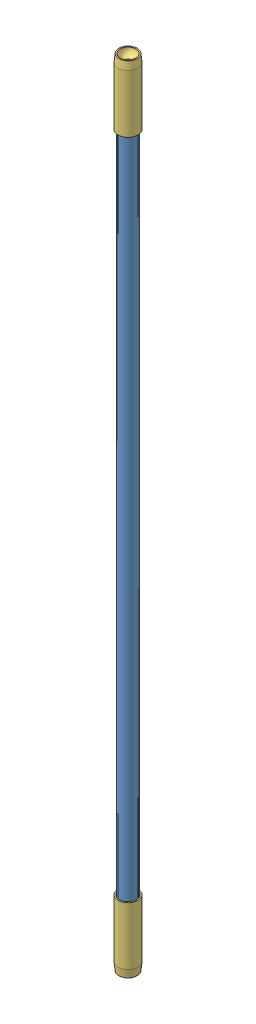
SolidWorks assembly Assem-Arms, configuration Default. Lengths in mm.
Overall size (16.54 480.57 16.54).
5 component instances, 3 part files, 10 mates.
Components (placement in the parent):
- part-dragon plate-carbon fiber tube-1: part-dragon plate-carbon fiber tube [Default] at (208.0008 -4.057 490.0421) size (9.95 452 9.95)
- part-3 8 in magnet-N52-1: part-3 8 in magnet-N52 [Default] at (208.0008 447.943 490.0421) size (9.53 9.53 9.53)
- part-3 8 in magnet-N52-2: part-3 8 in magnet-N52 [Default] at (208.0008 -4.057 490.0421) x (-1 0 0) z (0 0 1) size (9.53 9.53 9.53)
- PlasPrint-arm ends-1: PlasPrint-arm ends [Default] at (208.0008 422.468 490.0421) x (0.979 0 0.203858) z (-0.203858 0 0.979) size (12 39.76 12)
- PlasPrint-arm ends-2: PlasPrint-arm ends [Default] at (208.0008 21.418 490.0421) x (0.531956 0 0.846772) z (0.846772 0 -0.531956) size (12 39.76 12)
Mates (geometry in assembly coordinates):
- Concentric1: concentric aligned: cylinder of part-3 8 in magnet-N52-1 through (208.0008 457.468 490.0421) axis (0 -1 0) radius 4.7625; cylinder of PlasPrint-arm ends-1 through (208.0008 447.468 490.0421) axis (0 -1 0) radius 5.2
- Concentric2: concentric aligned: cylinder of part-3 8 in magnet-N52-1 through (208.0008 457.468 490.0421) axis (0 -1 0) radius 4.7625; cylinder of PlasPrint-arm ends-1 through (208.0008 447.468 490.0421) axis (0 -1 0) radius 6
- Concentric3: concentric aligned: cylinder of part-3 8 in magnet-N52-2 through (208.0008 -13.582 490.0421) axis (0 1 0) radius 4.7625; cylinder of PlasPrint-arm ends-2 through (208.0008 -3.582 490.0421) axis (0 1 0) radius 5.2
- Concentric4: concentric anti-aligned: cylinder of part-dragon plate-carbon fiber tube-1 through (208.0008 447.943 490.0421) axis (0 -1 0) radius 4.975; cylinder of PlasPrint-arm ends-2 through (208.0008 -3.582 490.0421) axis (0 1 0) radius 5.2
- Concentric5: concentric aligned: cylinder of part-dragon plate-carbon fiber tube-1 through (208.0008 447.943 490.0421) axis (0 -1 0) radius 4.975; cylinder of PlasPrint-arm ends-1 through (208.0008 447.468 490.0421) axis (0 -1 0) radius 5.2
- Coincident3: coincident anti-aligned: plane of part-dragon plate-carbon fiber tube-1 through (208.0008 447.943 490.0421) normal (0 1 0); plane of part-3 8 in magnet-N52-1 through (208.0008 447.943 490.0421) normal (0 -1 0)
- Coincident5: coincident anti-aligned: plane of part-dragon plate-carbon fiber tube-1 through (208.0008 -4.057 490.0421) normal (0 -1 0); plane of part-3 8 in magnet-N52-2 through (208.0008 -4.057 490.0421) normal (0 1 0)
- Parallel1: parallel anti-aligned: plane of part-3 8 in magnet-N52-1 through (208.0008 457.468 490.0421) normal (0 1 0); plane of PlasPrint-arm ends-1 through (207.6828 457.468 491.5691) normal (0 -1 0)
- Coincident7: coincident anti-aligned: circle of part-3 8 in magnet-N52-1; plane of PlasPrint-arm ends-1 through (207.6828 457.468 491.5691) normal (0 -1 0)
- Coincident8: coincident anti-aligned: plane of part-3 8 in magnet-N52-2 through (208.0008 -13.582 490.0421) normal (0 -1 0); plane of PlasPrint-arm ends-2 through (209.3215 -13.582 489.2124) normal (0 1 0)
